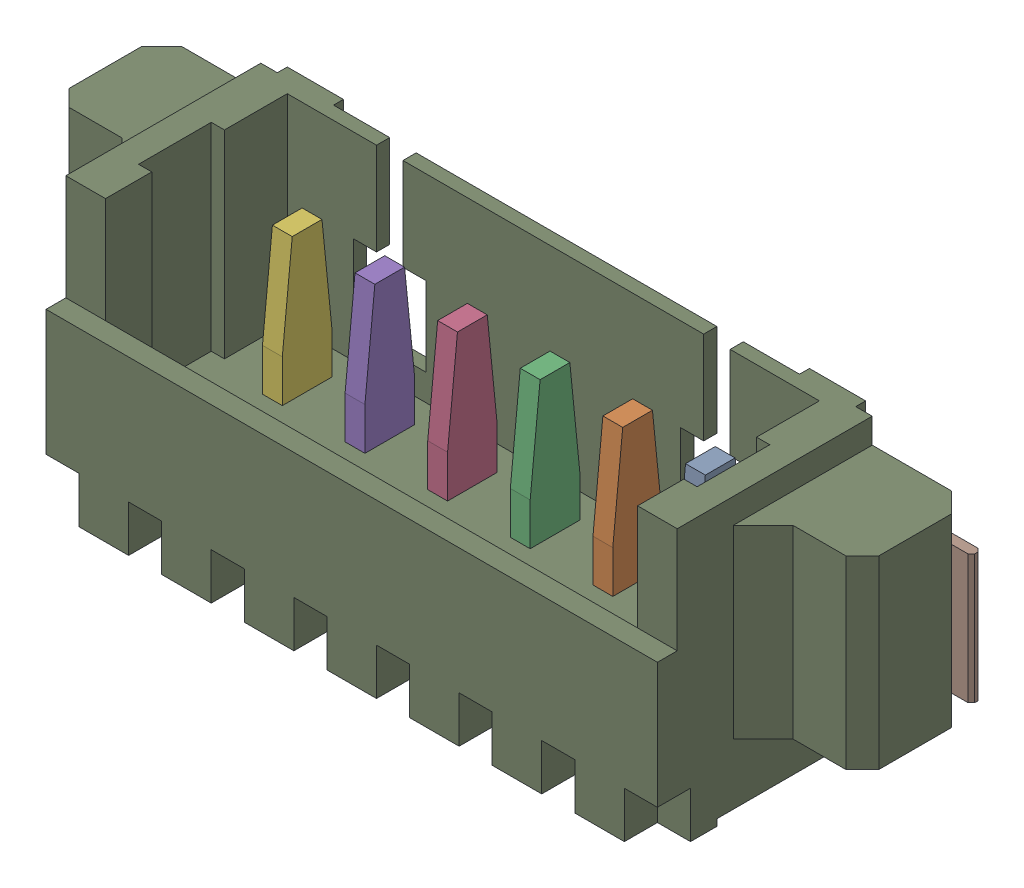
SolidWorks assembly J14, configuration Default. Lengths in mm.
Overall size (12.25 5.4 3.41).
10 component instances, 3 part files, 0 mates.
Components (placement in the parent):
- 653106131822-1: 653106131822 [Default] at (127.7501 84.1 1.69) x (-1 0 0) z (0 0 1) size (12.25 5.4 3.41)
  - 6531xx131822_PIN-1: 6531xx131822_PIN [Default] at (-3.125 2.7 -0.425) x (1 0 0) z (0 -1 0) size (0.3 1.48 4.54)
  - 6531xx131822_PIN-2: 6531xx131822_PIN [Default] at (-1.875 2.7 -0.425) x (1 0 0) z (0 -1 0) size (0.3 1.48 4.54)
  - 6531xx131822_PIN-3: 6531xx131822_PIN [Default] at (-0.625 2.7 -0.425) x (1 0 0) z (0 -1 0) size (0.3 1.48 4.54)
  - 6531xx131822_PIN-4: 6531xx131822_PIN [Default] at (0.625 2.7 -0.425) x (1 0 0) z (0 -1 0) size (0.3 1.48 4.54)
  - 6531xx131822_PIN-5: 6531xx131822_PIN [Default] at (1.875 2.7 -0.425) x (1 0 0) z (0 -1 0) size (0.3 1.48 4.54)
  - 6531xx131822_PIN-6: 6531xx131822_PIN [Default] at (3.125 2.7 -0.425) x (1 0 0) z (0 -1 0) size (0.3 1.48 4.54)
  - 6531xx131822_PIN_FLANGE-1: 6531xx131822_PIN_FLANGE [Default] at (5 -0.045 -1.05) size (1.25 1.95 1.4)
  - 6531xx131822_PIN_FLANGE-2: 6531xx131822_PIN_FLANGE [Default] at (-5 -0.045 -1.05) x (-1 0 0) z (0 0 1) size (1.25 1.95 1.4)
  - 653106131822-1: 653106131822 [Default] at origin size (12.25 4.2 3.4)
